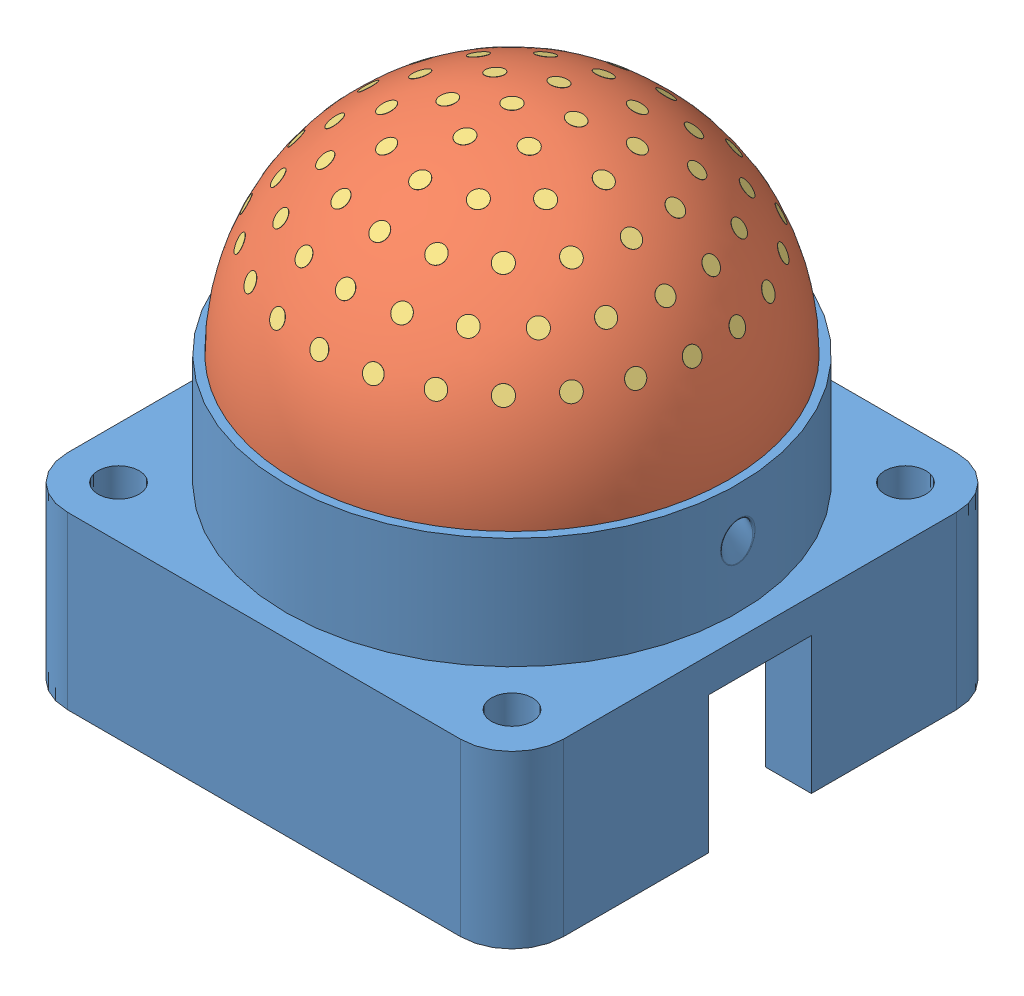
SolidWorks assembly tactile_dome, configuration Default. Lengths in mm.
Overall size (29 29.2 29).
8 component instances, 6 part files, 2 mates.
Components (placement in the parent):
- tactile_dome_outer-1: tactile_dome_outer [Default] at origin size (29 29.2 29)
  - dome_outer_rigidframe-1: dome_outer_rigidframe [Default] at origin size (29 16.65 29)
  - dome_outer_gel-1: dome_outer_gel [Default] at origin size (25.4 12.69 25.4)
  - dome_outer_markers-1: dome_outer_markers [Default] at origin size (22.95 7.51 22.91)
- tactile_dome_inner-1: tactile_dome_inner [Default] at origin size (23.66 14 23.66)
  - dome_inner_rigidframe-1: dome_inner_rigidframe [Default] at origin size (23.66 3 23.66)
  - dome_inner_gel-1: dome_inner_gel [Default] at origin size (22 10.99 22)
  - dome_inner_markers-1: dome_inner_markers [Default] at origin size (19.94 6.6 19.91)
Mates (geometry in assembly coordinates):
- Coincident1: coordinate: point of tactile_dome_outer-1
- Coincident2: coordinate: unknown of tactile_dome_inner-1
